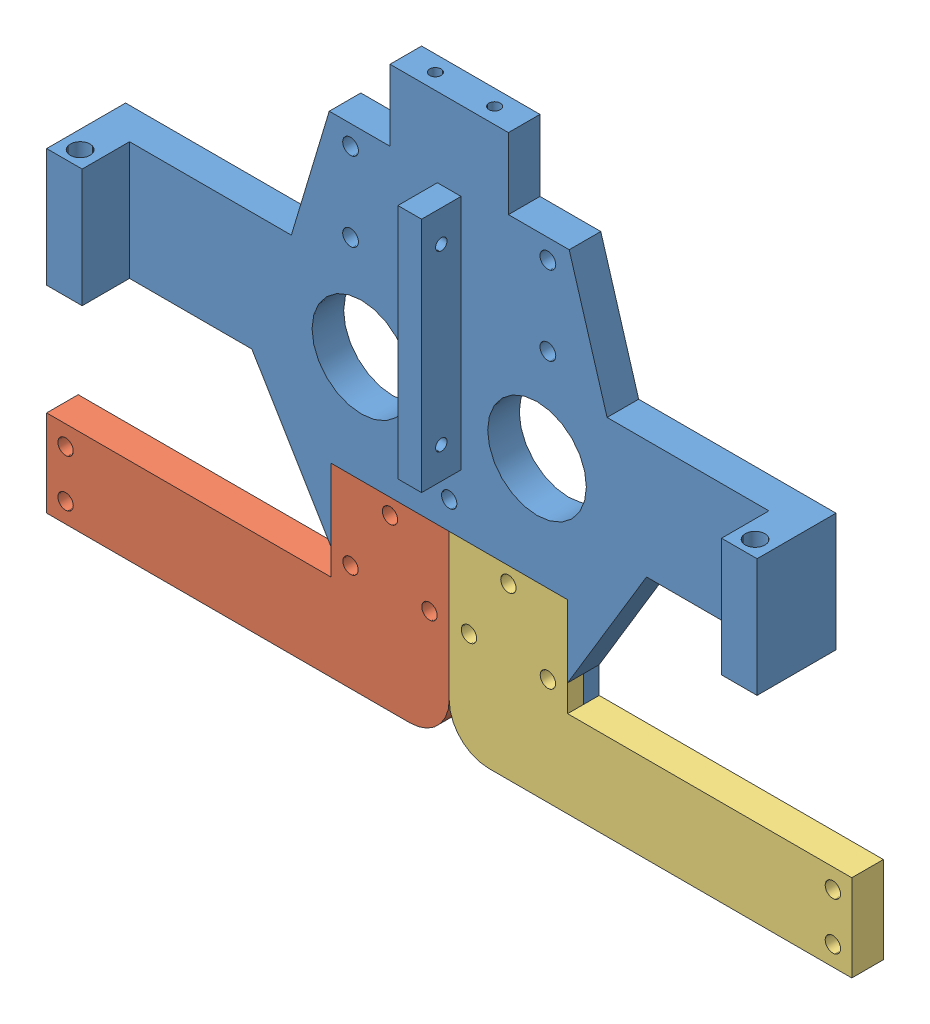
SolidWorks assembly back plate assm, configuration Default. Lengths in mm.
Overall size (204 142 20).
3 component instances, 3 part files, 4 mates.
Components (placement in the parent):
- back plate-1: back plate [Default] at origin size (180 120 20)
- back plate bottom mount R-1: back plate bottom mount R [Default] at (-51 -91 8) x (-1 0 0) z (0 0 -1) size (102 47 8)
- back plate bottom mount L-1: back plate bottom mount L [Default] at (51 -91 8) x (-1 0 0) z (0 0 -1) size (102 47 8)
Mates (geometry in assembly coordinates):
- Coincident1: coincident anti-aligned: circle of back plate-1; circle of back plate bottom mount R-1
- Coincident2: coincident anti-aligned: cylinder of back plate-1; circle of back plate bottom mount R-1
- Concentric1: concentric anti-aligned: cylinder of back plate-1; cylinder of back plate bottom mount L-1
- Coincident3: coincident aligned: circle of back plate-1; circle of back plate bottom mount L-1
